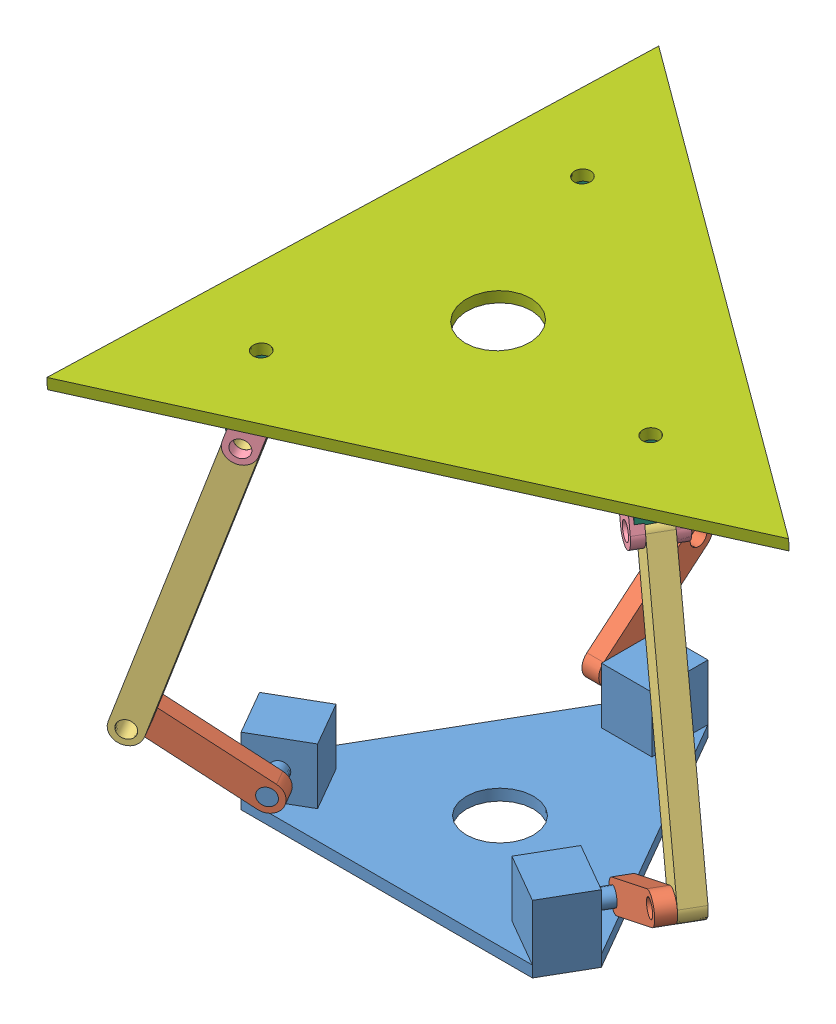
SolidWorks assembly ass1, configuration Default. Lengths in mm.
Overall size (478.97 417.7 497.87).
21 component instances, 7 part files, 64 mates.
Components (placement in the parent):
- base-1: base [Default] at (105.8362 141.7071 323.6046) size (305 60 281.37)
- link1-1: link1 [Default] at (-32.5132 201.7071 446.7819) x (0.433013 0.866025 -0.25) z (0.5 0 0.866025) size (25 125 15)
- link1-2: link1 [Default] at (281.6856 201.7071 381.83) x (-0.433013 0.866025 -0.25) z (0.5 0 -0.866025) size (25 125 15)
- link1-3: link1 [Default] at (68.3362 208.8465 147.2009) x (0 0.766044 0.642788) z (-1 0 0) size (25 125 15)
- link2-1: link2 [Default] at (-29.0762 345.5948 462.1181) x (0.823678 -0.308878 -0.475551) z (0.5 0 0.866025) size (25 275 20)
- link2-2: link2 [Default] at (293.1263 345.5489 371.1148) x (-0.82336 -0.310007 -0.475367) z (0.5 0 -0.866025) size (25 275 20)
- link2-3: link2 [Default] at (53.3362 361.1365 143.378) x (0 -0.275834 0.961205) z (-1 0 0) size (25 275 20)
- conn-1: conn [Default] at (265.5399 478.6517 332.0938) x (-0.82336 -0.310007 -0.475367) z (0.5 0 -0.866025) size (25 55 10) (hidden)
- conn-2: conn [Default] at (250.5399 478.6517 358.0746) x (-0.82336 -0.310007 -0.475367) z (0.5 0 -0.866025) size (25 55 10)
- plus-1: plus [Default] at (256.5128 492.9127 338.429) x (-0.05338 -0.998099 -0.030819) z (0.5 0 -0.866025) size (20 60 60)
- u-1: u [Default] at (257.3795 520.3343 340.3147) x (-0.864379 0.061638 -0.499049) z (-0.501853 -0.043543 0.863856) size (40 45 35)
- conn-3: conn [Default] at (18.3733 478.7491 457.8171) x (0.823678 -0.308878 -0.475551) z (0.5 0 0.866025) size (25 55 10)
- plus-2: plus [Default] at (17.3857 493.0156 446.8403) x (-0.006072 0.999975 0.003506) z (0.5 0 0.866025) size (20 60 60)
- u-2: u [Default] at (18.2524 520.4372 448.726) x (-0.866004 -0.007011 0.499988) z (0.499043 -0.07514 0.863314) size (40 45 35)
- conn-4: conn [Default] at (3.3733 478.7491 431.8364) x (0.823678 -0.308878 -0.475551) z (0.5 0 0.866025) size (25 55 10)
- conn-5: conn [Default] at (33.3362 495.7053 181.9948) x (0 -0.275834 0.961205) z (-1 0 0) size (25 55 10)
- plus-3: plus [Default] at (43.3362 510.1234 186.1323) x (0 0.997644 0.068604) z (-1 0 0) size (20 60 60)
- u-3: u [Default] at (44.2029 537.5449 188.018) x (0 0.068604 -0.997644) z (-0.999503 0.031442 0.002162) size (40 45 35)
- conn-6: conn [Default] at (63.3362 495.7053 181.9948) x (0 -0.275834 0.961205) z (-1 0 0) size (25 55 10)
- plate-4: plate [Default] at (106.6116 526.1055 325.6862) x (0.999503 -0.031472 -0.001727) z (-0.000436 -0.068591 0.997645) size (455.52 10 497.57)
- conn-7: conn [Default] at (270.5399 478.6517 323.4336) x (0.82336 0.310007 0.475367) z (-0.5 0 0.866025) size (25 55 10)
Mates (geometry in assembly coordinates):
- Concentric1: concentric aligned: cylinder of base-1 through (12.4868 176.7071 438.1217) axis (-0.5 0 -0.866025) radius 7.5; cylinder of link1-1 through (12.4868 176.7071 438.1217) axis (-0.5 0 -0.866025) radius 7.5
- Coincident1: coincident aligned: plane of base-1 through (12.4868 176.7071 438.1217) normal (0.5 0 0.866025); plane of link1-1 through (12.4868 176.7071 438.1217) normal (0.5 0 0.866025)
- Concentric2: concentric aligned: cylinder of base-1 through (251.6856 176.7071 347.189) axis (-0.5 0 0.866025) radius 7.5; cylinder of link1-2 through (251.6856 176.7071 347.189) axis (-0.5 0 0.866025) radius 7.5
- Coincident2: coincident anti-aligned: circle of base-1; plane of link1-2 through (251.6856 176.7071 347.189) normal (0.5 0 -0.866025)
- Concentric3: concentric aligned: cylinder of base-1 through (53.3362 176.7071 185.5032) axis (1 0 0) radius 7.5; cylinder of link1-3 through (53.3362 176.7071 185.5032) axis (1 0 0) radius 7.5
- Coincident3: coincident aligned: plane of base-1 through (53.3362 176.7071 185.5032) normal (-1 0 0); plane of link1-3 through (53.3362 176.7071 185.5032) normal (-1 0 0)
- Concentric4: concentric aligned: cylinder of link1-1 through (-62.5132 226.7071 481.4229) axis (-0.5 0 -0.866025) radius 7.5; cylinder of link2-1 through (-52.5132 226.7071 498.7435) axis (-0.5 0 -0.866025) radius 7.5
- Coincident4: coincident anti-aligned: plane of link1-1 through (12.4868 176.7071 438.1217) normal (0.5 0 0.866025); plane of link2-1 through (-62.5132 226.7071 481.4229) normal (-0.5 0 -0.866025)
- Concentric5: concentric aligned: cylinder of link1-2 through (326.6856 226.7071 390.4903) axis (-0.5 0 0.866025) radius 7.5; cylinder of link2-2 through (336.6856 226.7071 373.1698) axis (-0.5 0 0.866025) radius 7.5
- Coincident5: coincident anti-aligned: plane of link1-2 through (251.6856 176.7071 347.189) normal (0.5 0 -0.866025); plane of link2-2 through (326.6856 226.7071 390.4903) normal (-0.5 0 0.866025)
- Concentric6: concentric aligned: cylinder of link1-3 through (53.3362 240.9859 108.8987) axis (1 0 0) radius 7.5; cylinder of link2-3 through (33.3362 240.9859 108.8987) axis (1 0 0) radius 7.5
- Coincident6: coincident anti-aligned: plane of link1-3 through (53.3362 176.7071 185.5032) normal (-1 0 0); plane of link2-3 through (53.3362 240.9859 108.8987) normal (1 0 0)
- Concentric7: concentric aligned: cylinder of link2-2 through (269.5671 464.3907 334.4189) axis (-0.5 0 0.866025) radius 7.5; cylinder of conn-1 through (274.5671 464.3907 325.7586) axis (-0.5 0 0.866025) radius 7.5
- Coincident8: coincident anti-aligned: plane of link2-2 through (336.6856 226.7071 373.1698) normal (0.5 0 -0.866025); plane of conn-1 through (269.5671 464.3907 334.4189) normal (-0.5 0 0.866025)
- Concentric8: concentric aligned: cylinder of conn-1 through (274.5671 464.3907 325.7586) axis (-0.5 0 0.866025) radius 7.5; cylinder of conn-2 through (259.5671 464.3907 351.7394) axis (-0.5 0 0.866025) radius 7.5
- Coincident9: coincident anti-aligned: plane of link2-2 through (326.6856 226.7071 390.4903) normal (-0.5 0 0.866025); plane of conn-2 through (259.5671 464.3907 351.7394) normal (0.5 0 -0.866025)
- Concentric9: concentric aligned: cylinder of conn-1 through (266.5128 492.9127 321.1085) axis (-0.5 0 0.866025) radius 7.5; cylinder of plus-1 through (271.5128 492.9127 312.4483) axis (-0.5 0 0.866025) radius 7.5
- Concentric10: concentric aligned: cylinder of conn-2 through (251.5128 492.9127 347.0893) axis (-0.5 0 0.866025) radius 7.5; cylinder of plus-1 through (271.5128 492.9127 312.4483) axis (-0.5 0 0.866025) radius 7.5
- Coincident11: coincident anti-aligned: plane of conn-1 through (269.5671 464.3907 334.4189) normal (-0.5 0 0.866025); plane of plus-1 through (261.5128 492.9127 329.7688) normal (0.5 0 -0.866025)
- Concentric11: concentric anti-aligned: cylinder of plus-1 through (230.5815 494.7618 323.4575) axis (0.864379 -0.061638 0.499049) radius 7.5; cylinder of u-1 through (273.8004 491.68 348.41) axis (-0.864379 0.061638 -0.499049) radius 7.5
- Coincident12: coincident anti-aligned: plane of plus-1 through (247.869 493.5291 333.4385) normal (-0.864379 0.061638 -0.499049); plane of u-1 through (238.5351 475.317 347.356) normal (0.864379 -0.061638 0.499049)
- Concentric12: concentric aligned: cylinder of conn-3 through (19.3609 464.4826 468.794) axis (-0.5 0 -0.866025) radius 7.5; cylinder of conn-4 through (4.3609 464.4826 442.8132) axis (-0.5 0 -0.866025) radius 7.5
- Concentric13: concentric aligned: cylinder of conn-3 through (27.3857 493.0156 464.1608) axis (-0.5 0 -0.866025) radius 7.5; cylinder of plus-2 through (32.3857 493.0156 472.8211) axis (-0.5 0 -0.866025) radius 7.5
- Concentric14: concentric aligned: cylinder of plus-2 through (32.3857 493.0156 472.8211) axis (-0.5 0 -0.866025) radius 7.5; cylinder of conn-4 through (12.3857 493.0156 438.1801) axis (-0.5 0 -0.866025) radius 7.5
- Coincident14: coincident anti-aligned: plane of conn-3 through (14.3609 464.4826 460.1337) normal (-0.5 0 -0.866025); plane of plus-2 through (22.3857 493.0156 455.5006) normal (0.5 0 0.866025)
- Concentric15: concentric anti-aligned: cylinder of plus-2 through (-8.5944 492.8053 461.8399) axis (0.866004 0.007011 -0.499988) radius 7.5; cylinder of u-2 through (34.7058 493.1558 436.8406) axis (-0.866004 -0.007011 0.499988) radius 7.5
- Coincident15: coincident anti-aligned: plane of plus-2 through (8.7257 492.9455 451.8402) normal (-0.866004 -0.007011 0.499988); plane of u-2 through (16.9074 474.1805 465.7482) normal (0.866004 0.007011 -0.499988)
- Concentric16: concentric aligned: cylinder of link2-1 through (14.3609 464.4826 460.1337) axis (-0.5 0 -0.866025) radius 7.5; cylinder of conn-3 through (19.3609 464.4826 468.794) axis (-0.5 0 -0.866025) radius 7.5
- Coincident16: coincident anti-aligned: plane of link2-1 through (-52.5132 226.7071 498.7435) normal (0.5 0 0.866025); plane of conn-3 through (14.3609 464.4826 460.1337) normal (-0.5 0 -0.866025)
- Coincident17: coincident anti-aligned: plane of link2-1 through (-62.5132 226.7071 481.4229) normal (-0.5 0 -0.866025); plane of conn-4 through (4.3609 464.4826 442.8132) normal (0.5 0 0.866025)
- Concentric17: concentric aligned: cylinder of conn-5 through (23.3362 481.2872 177.8572) axis (1 0 0) radius 7.5; cylinder of conn-6 through (53.3362 481.2872 177.8572) axis (1 0 0) radius 7.5
- Concentric18: concentric aligned: cylinder of conn-5 through (23.3362 510.1234 186.1323) axis (1 0 0) radius 7.5; cylinder of plus-3 through (13.3362 510.1234 186.1323) axis (1 0 0) radius 7.5
- Concentric19: concentric aligned: cylinder of plus-3 through (13.3362 510.1234 186.1323) axis (1 0 0) radius 7.5; cylinder of conn-6 through (53.3362 510.1234 186.1323) axis (1 0 0) radius 7.5
- Coincident18: coincident anti-aligned: plane of conn-5 through (33.3362 481.2872 177.8572) normal (1 0 0); plane of plus-3 through (33.3362 510.1234 186.1323) normal (-1 0 0)
- Concentric20: concentric anti-aligned: cylinder of plus-3 through (43.3362 512.1815 156.2029) axis (0 -0.068604 0.997644) radius 7.5; cylinder of u-3 through (43.3362 508.7513 206.0851) axis (0 0.068604 -0.997644) radius 7.5
- Coincident19: coincident anti-aligned: plane of plus-3 through (43.3362 510.8094 176.1558) normal (0 0.068604 -0.997644); plane of u-3 through (25.2934 493.9095 174.9937) normal (0 -0.068604 0.997644)
- Concentric21: concentric aligned: cylinder of link2-3 through (33.3362 481.2872 177.8572) axis (1 0 0) radius 7.5; cylinder of conn-5 through (23.3362 481.2872 177.8572) axis (1 0 0) radius 7.5
- Coincident20: coincident anti-aligned: plane of link2-3 through (33.3362 240.9859 108.8987) normal (-1 0 0); plane of conn-5 through (33.3362 481.2872 177.8572) normal (1 0 0)
- Coincident21: coincident anti-aligned: plane of link2-3 through (53.3362 240.9859 108.8987) normal (1 0 0); plane of conn-6 through (53.3362 481.2872 177.8572) normal (-1 0 0)
- Parallel2: parallel aligned: plane of base-1 through (19.1375 201.7071 399.6409) normal (0.866025 0 -0.5); plane of link1-1
- Parallel17: parallel aligned: plane of link1-1; plane of link2-1
- Parallel3: parallel aligned: plane of base-1 through (105.8362 151.7071 323.6046) normal (0 1 0); plane of u-2
- Parallel6: parallel aligned: plane of conn-3; plane of u-2
- Parallel8: parallel aligned: plane of base-1 through (235.8362 151.7071 424.6409) normal (0.866025 0 0.5); plane of link1-2
- Parallel9: parallel aligned: plane of link1-2; plane of link2-2
- Parallel11: parallel aligned: plane of link2-2; plane of u-1 through (265.2561 539.2071 363.6842) normal (0.866025 0 0.5)
- Parallel13: parallel anti-aligned: plane of base-1 through (128.3362 151.7071 160.5032) normal (0 0 -1); plane of link1-3
- Parallel15: parallel aligned: plane of link1-3; plane of link2-3
- Parallel16: parallel aligned: plane of link2-3 through (33.3362 276.7071 173.0032) normal (0 0 -1); plane of u-3 through (25.8362 584.2071 165.5032) normal (0 0 -1)
- Concentric32: concentric aligned: cylinder of u-3 through (44.2029 537.5449 188.018) axis (-0.031516 -0.997148 -0.06857) radius 7.5; cylinder of plate-4 through (44.5181 547.5164 188.7037) axis (-0.031516 -0.997148 -0.06857) radius 7.5
- Concentric33: concentric aligned: cylinder of u-2 through (18.2524 520.4372 448.726) axis (-0.031516 -0.997148 -0.06857) radius 7.5; cylinder of plate-4 through (18.5676 530.4087 449.4117) axis (-0.031516 -0.997148 -0.06857) radius 7.5
- Concentric34: concentric aligned: cylinder of u-1 through (257.3795 520.3343 340.3147) axis (-0.031516 -0.997148 -0.06857) radius 7.5; cylinder of plate-4 through (257.6947 530.3058 341.0004) axis (-0.031516 -0.997148 -0.06857) radius 7.5
- Coincident52: coincident anti-aligned: plane of u-2 through (44.3058 519.2625 453.8342) normal (0.031516 0.997148 0.06857); plane of plate-4 through (106.6116 526.1055 325.6862) normal (-0.031516 -0.997148 -0.06857)
- Coincident53: coincident aligned: plane of u-1 through (265.8847 518.3395 365.4132) normal (0.031516 0.997148 0.06857); plane of u-3 through (26.7116 536.7231 208.0087) normal (0.031516 0.997148 0.06857)
- Coincident54: coincident aligned: plane of u-2 through (44.3058 519.2625 453.8342) normal (0.031516 0.997148 0.06857); plane of u-3 through (26.7116 536.7231 208.0087) normal (0.031516 0.997148 0.06857)
- Parallel4: parallel aligned: plane of link2-1 through (-42.2172 222.8462 492.7991) normal (0.823678 -0.308878 -0.475551); plane of conn-3 through (29.6568 460.6216 462.8496) normal (0.823678 -0.308878 -0.475551)
- Parallel10: parallel aligned: plane of link2-2 through (346.9776 230.5822 379.1119) normal (0.82336 0.310007 0.475367); plane of conn-1 through (284.8591 468.2658 331.7007) normal (0.82336 0.310007 0.475367)
- Parallel18: parallel aligned: plane of link2-3 through (33.3362 244.4338 96.8837) normal (0 0.275834 -0.961205); plane of conn-5 through (23.3362 484.7351 165.8422) normal (0 0.275834 -0.961205)
- B2: planar angle = 2.094395 rad aligned: line of link1-1 through (17.8995 187.5324 434.9967) axis (-0.75 0.5 0.433013); line of base-1 through (19.1375 201.7071 399.6409) axis (0 -1 0)
- B1: planar angle = 1.047198 rad aligned: plane of link1-2 through (257.0982 165.8818 350.314) normal (0.433013 -0.866025 0.25); plane of base-1 through (235.8362 151.7071 424.6409) normal (0.866025 0 0.5)
- B3: planar angle = 4.014257 rad aligned: line of base-1 through (83.3362 201.7071 210.5032) axis (0 -1 0); line of link1-3 through (53.3362 186.2827 193.538) axis (0 0.642788 -0.766044)
- Concentric35: concentric anti-aligned: cylinder of link2-2 through (269.5671 464.3907 334.4189) axis (-0.5 0 0.866025) radius 7.5; cylinder of conn-7 through (269.5671 464.3907 334.4189) axis (0.5 0 -0.866025) radius 7.5
- Coincident55: coincident anti-aligned: plane of link2-2 through (336.6856 226.7071 373.1698) normal (0.5 0 -0.866025); plane of conn-7 through (269.5671 464.3907 334.4189) normal (-0.5 0 0.866025)
- Concentric36: concentric anti-aligned: cylinder of plus-1 through (271.5128 492.9127 312.4483) axis (-0.5 0 0.866025) radius 7.5; cylinder of conn-7 through (261.5128 492.9127 329.7688) axis (0.5 0 -0.866025) radius 7.5
